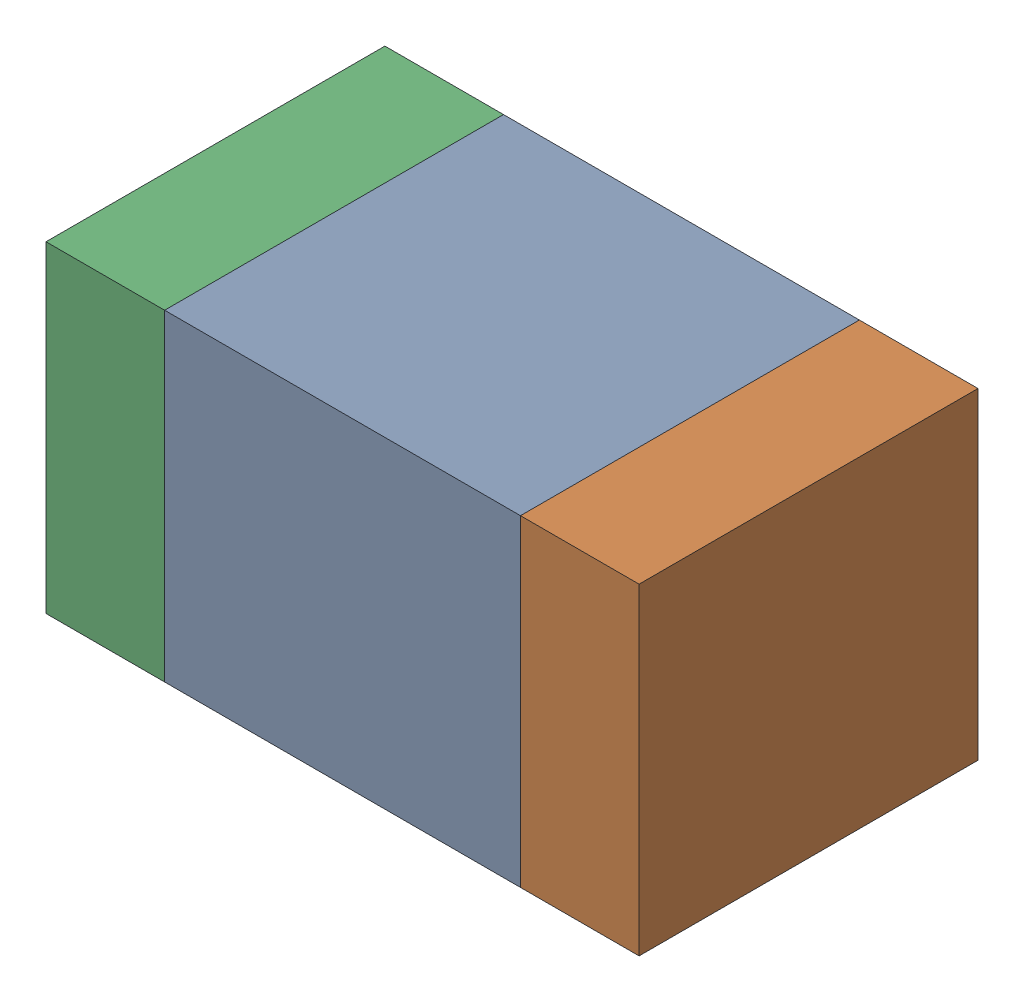
SolidWorks assembly C317_1PCB, configuration Default. Lengths in mm.
Overall size (1.75 0.95 1).
6 component instances, 2 part files, 0 mates.
Components (placement in the parent):
- 761616112-1: 761616112 [Default] at (127.6 118.2 -2.6638) size (1.05 0.95 1)
  - Extruded_14-1: Extruded_14 [Default] at origin size (1.05 0.95 1)
- 761616248-1: 761616248 [Default] at (128.3 118.2 -2.6638) size (0.35 0.95 1)
  - Extruded_15-1: Extruded_15 [Default] at origin size (0.35 0.95 1)
- 761616248-2: 761616248 [Default] at (126.9 118.2 -2.6638) size (0.35 0.95 1)
  - Extruded_15-1: Extruded_15 [Default] at origin size (0.35 0.95 1)
